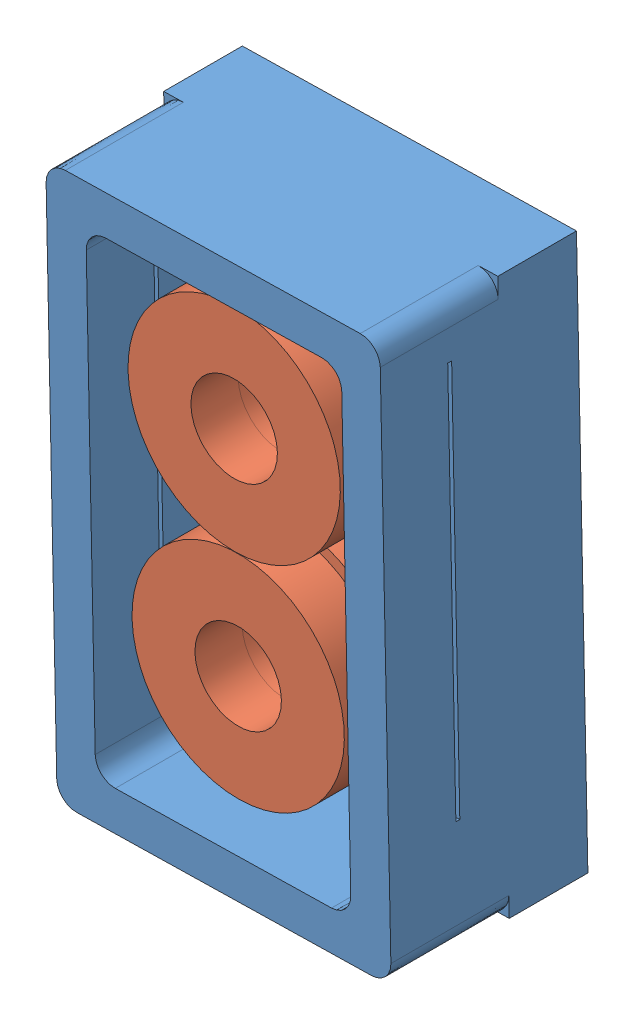
SolidWorks assembly Assem1, configuration Default. Lengths in mm.
Overall size (22.32 36 14.03).
4 component instances, 3 part files, 5 mates.
Components (placement in the parent):
- Holder-1: Holder [Default] at (-22.3081 22.7591 37.0137) x (0.999785 0.02075 0) z (0 0 1) size (21.59 35.56 12.7)
- WheelTreads1-1: WheelTreads1 [Default] at (-20.9903 27.8381 45.6497) x (-0.923728 -0.383049 0) z (0 0 -1) size (13.72 13.72 6.6)
- WheelTreads1-2: WheelTreads1 [Default] at (-20.7313 14.119 45.6497) x (-0.923728 -0.383049 0) z (0 0 -1) size (13.72 13.72 6.6)
- [v2]MotorPinchRollInterface-2: [v2]MotorPinchRollInterface [Default] at (-21.0174 27.8956 45.2067) x (-0.923728 -0.383049 0) z (0 0 -1) size (4.57 4.57 9.53)
Mates (geometry in assembly coordinates):
- Coincident4: coincident anti-aligned: plane of Holder-1 through (-22.3081 22.7591 42.0937) normal (0 0 1); plane of WheelTreads1-2 through (-20.7313 14.119 42.0937) normal (0 0 -1)
- Coincident5: coincident anti-aligned: plane of Holder-1 through (-22.3081 22.7591 42.0937) normal (0 0 1); plane of WheelTreads1-1 through (-20.9903 27.8381 42.0937) normal (0 0 -1)
- Tangent1: tangent aligned: cylinder of Holder-1 through (-20.7328 14.1825 49.7137) axis (0 0 -1) radius 2.8575; cylinder of WheelTreads1-2 through (-20.7313 14.119 45.1417) axis (0 0 1) radius 2.794
- Tangent2: tangent aligned: cylinder of Holder-1 through (-21.0174 27.8956 49.7137) axis (0 0 -1) radius 2.8575; cylinder of WheelTreads1-1 through (-20.9903 27.8381 48.6977) axis (0 0 -1) radius 2.794
- Concentric7: concentric anti-aligned: cylinder of Holder-1 through (-21.0174 27.8956 49.7137) axis (0 0 -1) radius 2.8575; cylinder of [v2]MotorPinchRollInterface-2 through (-21.0174 27.8956 35.6817) axis (0 0 1) radius 2.286
